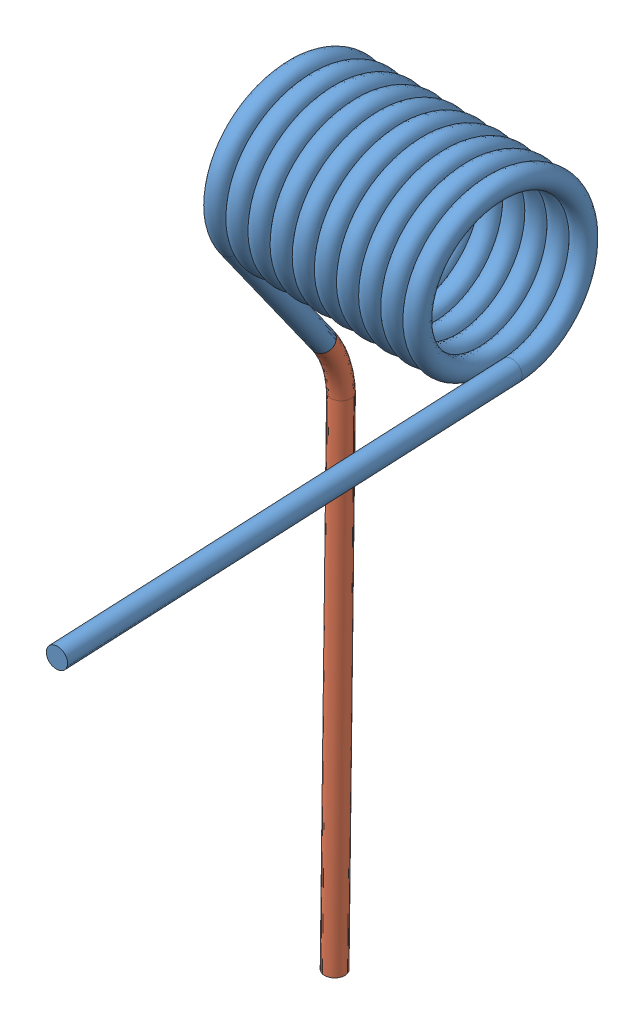
SolidWorks assembly Torsion Spring, configuration Default. Lengths in mm.
Overall size (5.28 12.67 11.91).
2 component instances, 2 part files, 1 mates.
Components (placement in the parent):
- 9271K269_Torsion Spring-1: 9271K269_Torsion Spring [9271K269] at (-8.4241 -9.0247 8.496) size (5.28 4.29 8.8)
- Spring Piece 2-1: Spring Piece 2 [Default] at (-11.7919 -11.7568 7.9396) x (0.997993 -0.010759 -0.062399) z (-0.045426 -0.808182 -0.587178) size (0.39 4.95 6.99)
Mates (geometry in assembly coordinates):
- Coincident3: coincident aligned: circle of 9271K269_Torsion Spring-1; circle of Spring Piece 2-1
